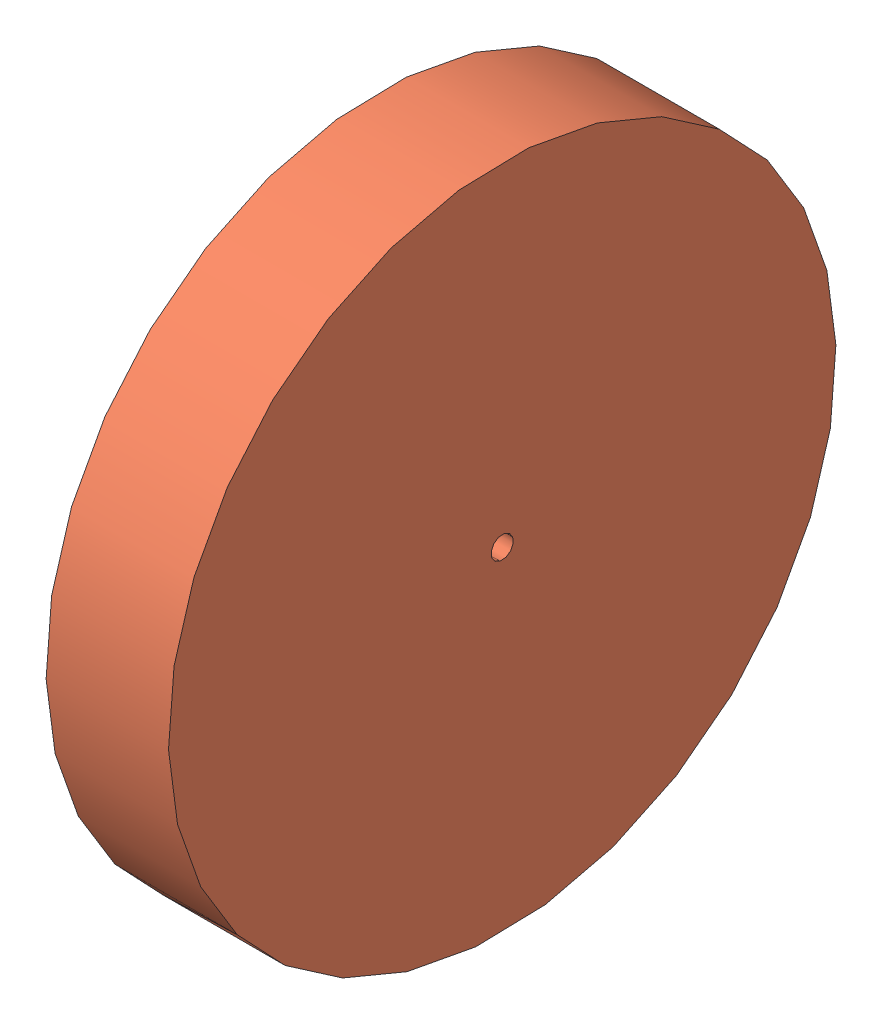
SolidWorks assembly Assemblage1, configuration Défaut. Lengths in mm.
Overall size (30 153.09 153.09).
2 component instances, 2 part files, 2 mates.
Components (placement in the parent):
- RoueDente_externe-1: RoueDente_externe [DIN - Spur gear 2M 10T 20PA 10FW ---S10B50H20L4.0N] at (-1.6381 0.4505 0) size (20 22.98 24)
- RoueDente_interne-1: RoueDente_interne [DIN - Internal spur gear 2M 50T 20PA 12FW ---S50S120OD 1.0AF] at (-3.6381 -1.4161 -25.5584) x (1 0 0) z (0 -0.943034 -0.332696) size (22 120 120)
Mates (geometry in assembly coordinates):
- Coïncidente2: coincident anti-aligned: plane of RoueDente_externe-1 through (8.3619 0.4505 0) normal (1 0 0); plane of RoueDente_interne-1 through (8.3619 -1.4161 -25.5584) normal (-1 0 0)
- Contr.Engrenages6: gear = 4 : 4 mm: circle of RoueDente_interne-1; circle of RoueDente_externe-1
